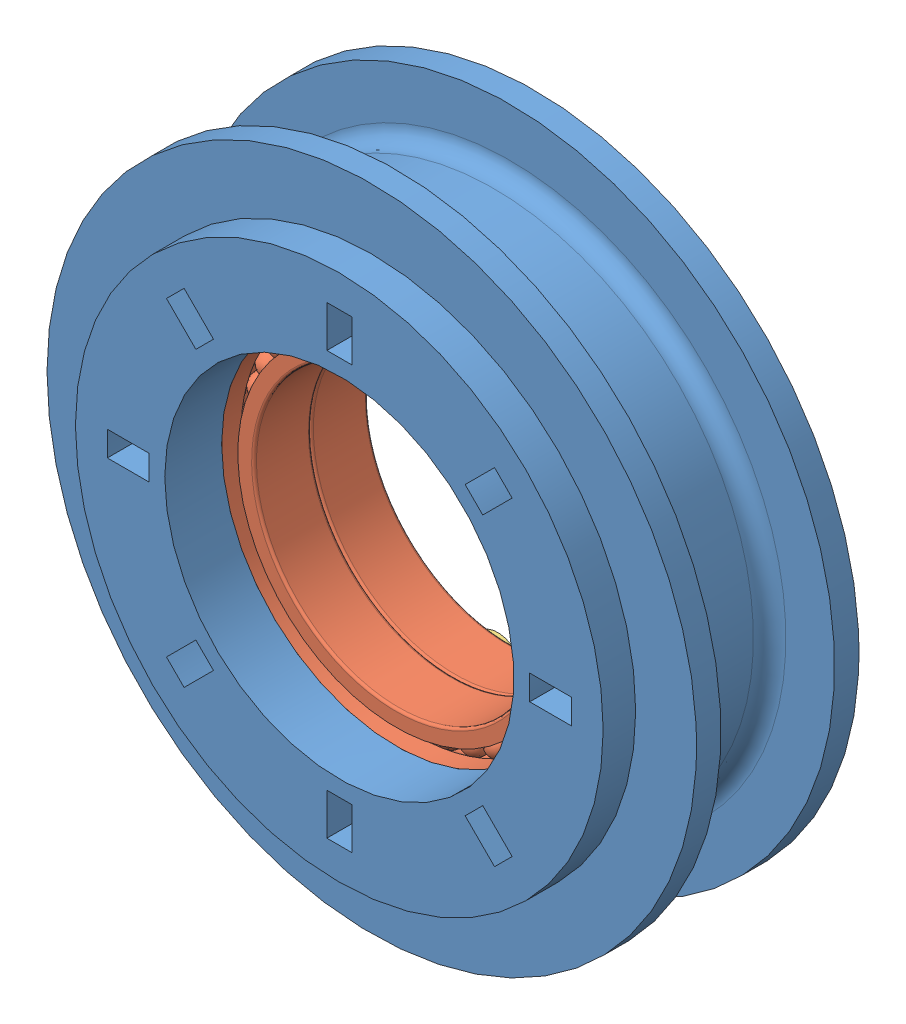
SolidWorks assembly 收卷轮, configuration 默认. Lengths in mm.
Overall size (70 70 24).
4 component instances, 3 part files, 5 mates.
Components (placement in the parent):
- 收卷轮1-1: 收卷轮1 [默认] at (34.4467 -0.1281 -2) size (70 70 24)
- deep groove ball bearings gb-4: deep groove ball bearings gb [Rolling bearings 61807 GB 276-94] at (34.4467 -0.1281 -5.5) x (0 0 -1) z (-0.450839 -0.892605 0) size (7 47 47)
- deep groove ball bearings gb-5: deep groove ball bearings gb [Rolling bearings 61807 GB 276-94] at (34.4467 -0.1281 1.5) x (0 0 -1) z (0.107289 0.994228 0) size (7 47 47)
- circlips for holes--type a gb-2: circlips for holes--type a gb [GB_CONNECTING_PIECE_RING_RRH 47] at (34.4467 -0.1281 -10.5) x (-0.923728 -0.383049 0) z (0 0 -1) size (50.5 48.58 1.5)
Mates (geometry in assembly coordinates):
- 同心31: concentric anti-aligned: cylinder of 收卷轮1-1 through (34.4467 -0.1281 8) axis (0 0 -1) radius 23.5; cylinder of deep groove ball bearings gb-5 through (34.4467 -0.1281 8.4714) axis (0 0 1) radius 17.5
- 同心41: concentric anti-aligned: cylinder of 收卷轮1-1 through (34.4467 -0.1281 8) axis (0 0 -1) radius 23.5; cylinder of deep groove ball bearings gb-4 through (34.4467 -0.1281 1.4714) axis (0 0 1) radius 17.5
- 重合41: coincident anti-aligned: plane of deep groove ball bearings gb-4 through (51.8525 -8.9194 -2) normal (0 0 1); plane of deep groove ball bearings gb-5 through (11.0823 2.3932 -2) normal (0 0 -1)
- 同心42: concentric aligned: cylinder of 收卷轮1-1 through (34.4467 -0.1281 8) axis (0 0 -1) radius 23.5; cylinder of circlips for holes--type a gb-2 through (34.4467 -0.1281 -9) axis (0 0 -1) radius 25.25
- 重合421: coincident anti-aligned: plane of 收卷轮1-1 through (34.4467 25.3719 -9) normal (0 0 -1); plane of circlips for holes--type a gb-2 through (34.4467 -0.1281 -9) normal (0 0 1)
